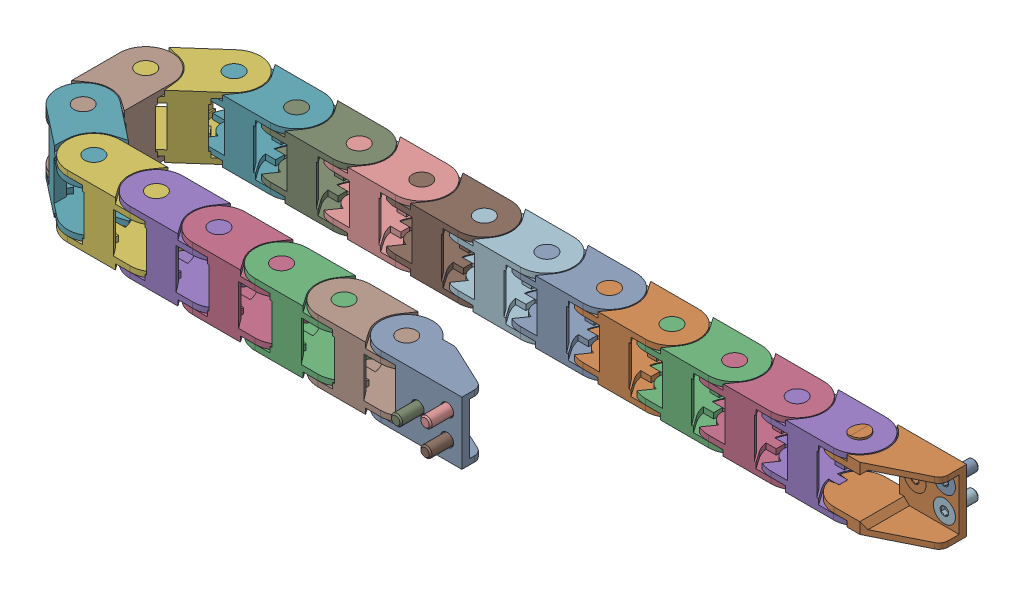
SolidWorks assembly 10x11 Chain Z, configuration Default. Lengths in mm.
Overall size (214.76 18 64.75).
26 component instances, 4 part files, 0 mates.
Components (placement in the parent):
- 10x11 Unfixed End v1 (1)-1: 10x11 Unfixed End v1 (1) [Default] at (0.785 0 36) x (-1 0 0) z (0 0 -1) size (29 17 14)
- 10x11 Fixed End v1 (1)-1: 10x11 Fixed End v1 (1) [Default] at (85.1252 17 -2.7505) x (-1 0 0) z (0 0 1) size (28.83 18 14)
- 10x11 Chain Link v1 (1)-1: 10x11 Chain Link v1 (1) [Default] at (-33.215 15.5 36) size (31.2 17 14.3)
- 10x11 Chain Link v1 (1)-2: 10x11 Chain Link v1 (1) [Default] at (-50.215 15.5 36) size (31.2 17 14.3)
- 10x11 Chain Link v1 (1)-3: 10x11 Chain Link v1 (1) [Default] at (-67.215 15.5 36) size (31.2 17 14.3)
- 10x11 Chain Link v1 (1)-4: 10x11 Chain Link v1 (1) [Default] at (-84.215 15.5 36) size (31.2 17 14.3)
- 10x11 Chain Link v1 (1)-5: 10x11 Chain Link v1 (1) [Default] at (-67.8748 15.5 -2.7505) x (-1 0 0) z (0 0 -1) size (31.2 17 14.3)
- 10x11 Chain Link v1 (1)-6: 10x11 Chain Link v1 (1) [Default] at (-97.5929 15.5 8.5104) x (0 0 1) z (-1 0 0) size (31.2 17 14.3)
- 10x11 Chain Link v1 (1)-7: 10x11 Chain Link v1 (1) [Default] at (-50.8748 15.5 -2.7505) x (-1 0 0) z (0 0 -1) size (31.2 17 14.3)
- 10x11 Chain Link v1 (1)-8: 10x11 Chain Link v1 (1) [Default] at (-33.8748 15.5 -2.7505) x (-1 0 0) z (0 0 -1) size (31.2 17 14.3)
- 10x11 Chain Link v1 (1)-9: 10x11 Chain Link v1 (1) [Default] at (-16.8748 15.5 -2.7505) x (-1 0 0) z (0 0 -1) size (31.2 17 14.3)
- 10x11 Chain Link v1 (1)-10: 10x11 Chain Link v1 (1) [Default] at (0.1252 15.5 -2.7505) x (-1 0 0) z (0 0 -1) size (31.2 17 14.3)
- 10x11 Chain Link v1 (1)-11: 10x11 Chain Link v1 (1) [Default] at (17.1252 15.5 -2.7505) x (-1 0 0) z (0 0 -1) size (31.2 17 14.3)
- 10x11 Chain Link v1 (1)-12: 10x11 Chain Link v1 (1) [Default] at (34.1252 15.5 -2.7505) x (-1 0 0) z (0 0 -1) size (31.2 17 14.3)
- 10x11 Chain Link v1 (1)-13: 10x11 Chain Link v1 (1) [Default] at (51.1252 15.5 -2.7505) x (-1 0 0) z (0 0 -1) size (31.2 17 14.3)
- 10x11 Chain Link v1 (1)-14: 10x11 Chain Link v1 (1) [Default] at (68.1252 15.5 -2.7505) x (-1 0 0) z (0 0 -1) size (31.2 17 14.3)
- 10x11 Chain Link v1 (1)-15: 10x11 Chain Link v1 (1) [Default] at (85.1252 15.5 -2.7505) x (-1 0 0) z (0 0 -1) size (31.2 17 14.3)
- 10x11 Chain Link v1 (1)-16: 10x11 Chain Link v1 (1) [Default] at (-84.8748 15.5 -2.7505) x (-0.748956 0 0.66262) z (-0.66262 0 -0.748956) size (31.2 17 14.3)
- 10x11 Chain Link v1 (1)-17: 10x11 Chain Link v1 (1) [Default] at (-97.5929 15.5 25.5104) x (0.786935 0 0.617036) z (-0.617036 0 0.786935) size (31.2 17 14.3)
- 10x11 Chain Link v1 (1)-18: 10x11 Chain Link v1 (1) [Default] at (-16.215 15.5 36) size (31.2 17 14.3)
- M3x8 FHCS (1)-1: M3x8 FHCS (1) [Default] at (10.785 8.5 41) x (-1 0 0) z (0 0 -1) size (6 6 8.12)
- M3x8 FHCS (1)-2: M3x8 FHCS (1) [Default] at (18.785 12 41) x (-1 0 0) z (0 0 -1) size (6 6 8.12)
- M3x8 FHCS (1)-3: M3x8 FHCS (1) [Default] at (18.785 5 41) x (-1 0 0) z (0 0 -1) size (6 6 8.12)
- M3x8 FHCS (1)-4: M3x8 FHCS (1) [Default] at (103.1252 5 -7.7505) x (-1 0 0) z (0 0 1) size (6 6 8.12)
- M3x8 FHCS (1)-5: M3x8 FHCS (1) [Default] at (103.1252 12 -7.7505) x (-1 0 0) z (0 0 1) size (6 6 8.12)
- M3x8 FHCS (1)-6: M3x8 FHCS (1) [Default] at (95.1252 8.5 -7.7505) x (-1 0 0) z (0 0 1) size (6 6 8.12)
